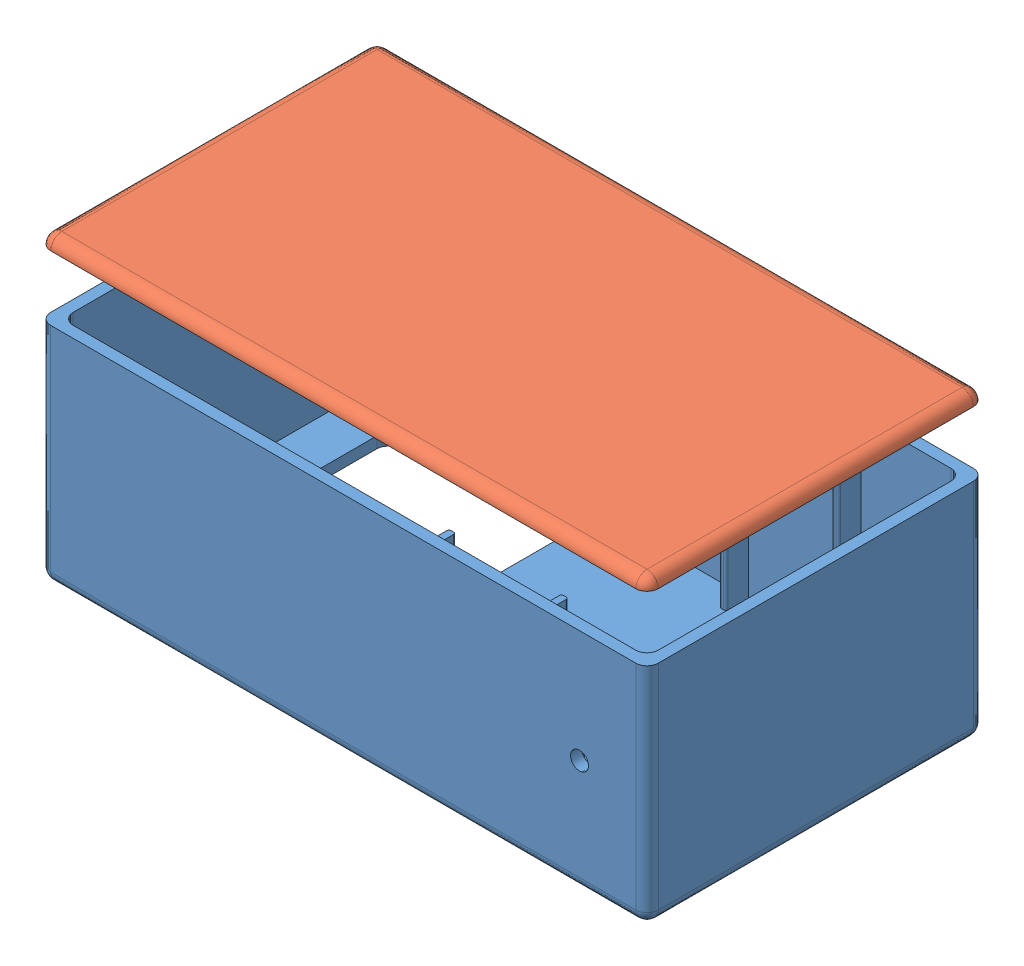
SolidWorks assembly FullCaseV01, configuration Default. Lengths in mm.
Overall size (270 133.66 150).
2 component instances, 2 part files, 2 mates.
Components (placement in the parent):
- CaseFrontV01-1: CaseFrontV01 [Default] at origin size (270 100 150)
- CaseBackV01-1: CaseBackV01 [Default] at (0 133.6627 0) x (1 0 0) z (0 0 -1) size (270 10 150)
Mates (geometry in assembly coordinates):
- Coincident2: coincident anti-aligned: plane of CaseFrontV01-1 through (130 5 -70) normal (0 0 1); plane of CaseBackV01-1 through (-130 123.6627 -70) normal (0 0 -1)
- Coincident3: coincident anti-aligned: plane of CaseFrontV01-1 through (130 5 70) normal (-1 0 0); plane of CaseBackV01-1 through (130 123.6627 -70) normal (1 0 0)
